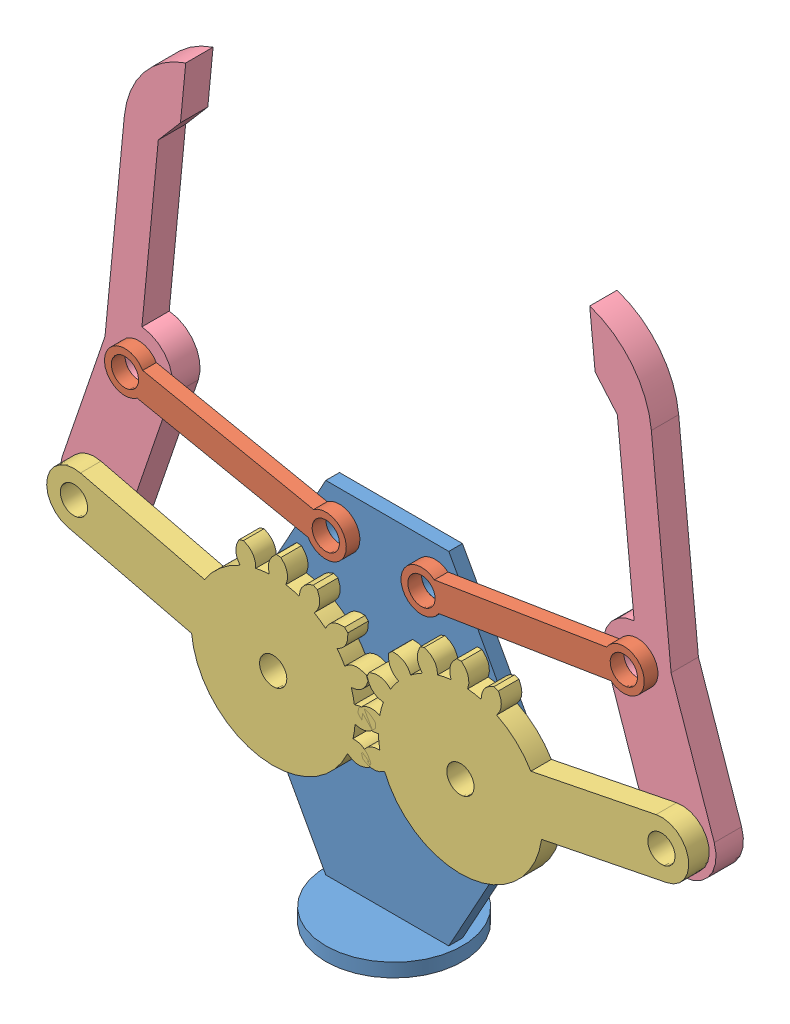
SolidWorks assembly jaw, configuration 默认. Lengths in mm.
Overall size (112.18 96.34 20).
7 component instances, 4 part files, 14 mates.
Components (placement in the parent):
- part1-1: part1 [默认] at origin size (40 52 20)
- part2-1: part2 [默认] at (21.8064 49.4022 1) x (0.987093 0.160147 0) z (0 0 1) size (36 6 2)
- part3-1: part3 [默认] at (-13.7 27 1) x (0.971614 -0.236572 0) z (0 0 1) size (48.96 26.8 3)
- part4-1: part4 [默认] at (-39.6186 43.5612 -3) x (0.322985 0.946404 0) z (0 0 1) size (66.62 17.14 4)
- part2-2: part2 [默认] at (-21.6944 50.0126 1) x (0.979624 -0.200841 0) z (0 0 1) size (36 6 2)
- part3-2: part3 [默认] at (13.7 27 4) x (-0.980529 -0.196373 0) z (0 0 -1) size (48.96 26.8 3)
- part4-2: part4 [默认] at (39.8643 42.3478 1) x (-0.325154 0.945661 0) z (0 0 -1) size (66.62 17.14 4)
Mates (geometry in assembly coordinates):
- 同心1: concentric anti-aligned: cylinder of part1-1 through (-13.7 27 -1) axis (0 0 1) radius 1.8367; cylinder of part3-1 through (-13.7 27 4) axis (0 0 -1) radius 2
- 同心2: concentric aligned: cylinder of part1-1 through (13.7 27 -1) axis (0 0 1) radius 1.9924; cylinder of part3-2 through (13.7 27 1) axis (0 0 1) radius 2
- 重合1: coincident anti-aligned: plane of part1-1 through (0 0 1) normal (0 0 1); plane of part3-2 through (13.7 27 1) normal (0 0 -1)
- 重合2: coincident anti-aligned: plane of part1-1 through (0 0 1) normal (0 0 1); plane of part3-1 through (-13.7 27 1) normal (0 0 -1)
- 同心3: concentric anti-aligned: cylinder of part1-1 through (-7 47 -1) axis (0 0 1) radius 2; cylinder of part2-2 through (-7 47 3) axis (0 0 -1) radius 2
- 重合3: coincident: plane of part1-1 through (0 0 1) normal (0 0 1); point of part2-2
- 同心4: concentric anti-aligned: cylinder of part1-1 through (7 47 -1) axis (0 0 1) radius 2; cylinder of part2-1 through (7 47 3) axis (0 0 -1) radius 2
- 重合5: coincident anti-aligned: plane of part1-1 through (0 0 1) normal (0 0 1); plane of part2-1 through (36.6128 51.8044 1) normal (0 0 -1)
- 同心5: concentric anti-aligned: cylinder of part4-1 through (-36.3887 53.0252 -3) axis (0 0 1) radius 2; cylinder of part2-2 through (-36.3887 53.0252 3) axis (0 0 -1) radius 2
- 同心6: concentric anti-aligned: cylinder of part3-1 through (-42.8484 34.0972 4) axis (0 0 -1) radius 2; cylinder of part4-1 through (-42.8484 34.0972 -3) axis (0 0 1) radius 2
- 重合6: coincident anti-aligned: plane of part3-1 through (-13.7 27 1) normal (0 0 -1); plane of part4-1 through (-36.3887 53.0252 1) normal (0 0 1)
- 重合7: coincident anti-aligned: plane of part3-2 through (13.7 27 1) normal (0 0 -1); plane of part4-2 through (36.6128 51.8044 1) normal (0 0 1)
- 同心9: concentric aligned: cylinder of part2-1 through (36.6128 51.8044 3) axis (0 0 -1) radius 2; cylinder of part4-2 through (36.6128 51.8044 1) axis (0 0 -1) radius 2
- 同心10: concentric anti-aligned: cylinder of part3-2 through (43.1159 32.8912 1) axis (0 0 1) radius 2; cylinder of part4-2 through (43.1159 32.8912 1) axis (0 0 -1) radius 2
